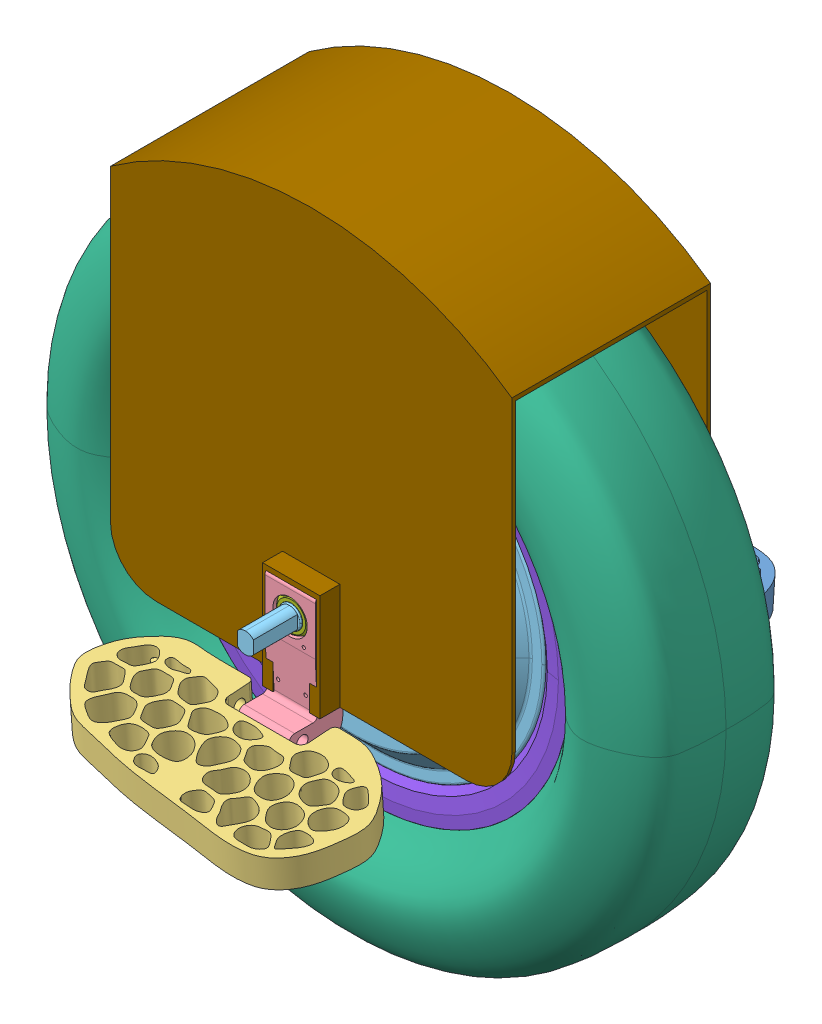
SolidWorks assembly ultimate_euc, configuration Default. Lengths in mm.
Overall size (694.47 596.2 979.3).
13 component instances, 9 part files, 13 mates.
Components (placement in the parent):
- Pedal subassembly-3: Pedal subassembly [Default] at (-129.9505 29.6673 -165.9174) x (0 -0.070149 -0.997537) z (1 0 0) size (667.71 138.3 546.6)
  - nylonove_pedals-1: nylonove_pedals [Default] at (-15.1911 -18.6389 -1.5417) size (641.26 25 546.6)
  - pedal holder solid-1: pedal holder solid [Default] at (-20.4641 -78.6432 -73.8896) x (1 0 0) z (0 -0.097811 0.995205) size (54.31 133.41 56.48)
- MirrorPedal subassembly-11: MirrorPedal subassembly [Default] at (-129.9505 29.6673 191.1591) x (0 -0.070149 0.997537) z (-1 0 0) size (157.12 138.3 257.31)
  - Mirrornylonove_pedals-1: Mirrornylonove_pedals [Default] at (-15.1911 -18.6389 1.5417) size (130.43 25 257.31)
  - Mirrorpedal holder solid-1: Mirrorpedal holder solid [Default] at (-20.4641 -78.6432 73.8896) x (1 0 0) z (0 0.097811 0.995205) size (54.31 133.41 56.48)
- 14in-1: 14in [Default] at (-128.8319 93.0936 9.2958) size (550.4 550.4 275) (flexible)
  - 14in QS273 6kW Scooter.stp[3]-1: 14in QS273 6kW Scooter.stp[3] [Default] at origin size (294.99 294.99 275)
  - 14in QS273 6kW Scooter.stp[5]-1: 14in QS273 6kW Scooter.stp[5] [Default] at origin size (550.4 550.4 140.93)
  - 14in QS273 6kW Scooter.stp[6]-1: 14in QS273 6kW Scooter.stp[6] [Default] at (0 0 -26.5) x (0.923728 0.383049 0) z (0 0 -1) size (31.1 30.88 15)
  - 14in QS273 6kW Scooter.stp[2]2-1: 14in QS273 6kW Scooter.stp[2]2 [Default] at origin size (350 350 83.1)
  - 14in QS273 6kW Scooter.stp[6]-2: 14in QS273 6kW Scooter.stp[6] [Default] at (0 0 33.15) size (31.1 30.88 15)
- Chassis-1: Chassis [Default] at (-203.8401 118.0936 165.2286) x (0 0 1) z (0 1 0) size (208 350 386)
Mates (geometry in assembly coordinates):
- Concentric1: concentric anti-aligned: cylinder of 14in-1/14in QS273 6kW Scooter.stp[3]-1 through (-128.8319 93.0936 134.0458) axis (0 0 1) radius 9; cylinder of MirrorPedal subassembly-11/Mirrorpedal holder solid-1 through (-128.8319 93.0936 134.2958) axis (0 0 -1) radius 7
- Concentric2: concentric aligned: cylinder of Pedal subassembly-3/pedal holder solid-1 through (-128.8319 93.0936 -109.0542) axis (0 0 1) radius 7; cylinder of 14in-1/14in QS273 6kW Scooter.stp[3]-1 through (-128.8319 93.0936 -102.4542) axis (0 0 1) radius 9
- Concentric3: concentric aligned: circle of 14in-1/14in QS273 6kW Scooter.stp[6]-1; cylinder of MirrorPedal subassembly-11/Mirrorpedal holder solid-1 through (-128.8319 93.0936 105.7958) axis (0 0 1) radius 15
- Concentric8: concentric aligned: cylinder of Pedal subassembly-3/pedal holder solid-1 through (-128.8319 93.0936 -80.5542) axis (0 0 -1) radius 15; circle of 14in-1/14in QS273 6kW Scooter.stp[6]-2
- Coincident2: coincident anti-aligned: plane of MirrorPedal subassembly-11/Mirrorpedal holder solid-1 through (-106.8319 94.0936 98.2958) normal (0 0 1); plane of 14in-1/14in QS273 6kW Scooter.stp[6]-1 through (-128.8319 93.0936 98.2958) normal (0 0 -1)
- Coincident3: coincident anti-aligned: plane of Pedal subassembly-3/pedal holder solid-1 through (-106.8319 94.0936 -73.0542) normal (0 0 -1); plane of 14in-1/14in QS273 6kW Scooter.stp[6]-2 through (-128.8319 93.0936 -73.0542) normal (0 0 1)
- Coincident4: coincident anti-aligned: plane of MirrorPedal subassembly-11/Mirrorpedal holder solid-1 through (-106.8319 18.0907 90.2958) normal (0 0 -1); plane of 14in-1/14in QS273 6kW Scooter.stp[3]-1 through (-103.8319 93.0936 90.2958) normal (0 0 1)
- Coincident5: coincident anti-aligned: plane of Pedal subassembly-3/pedal holder solid-1 through (-106.8319 18.0907 -65.0542) normal (0 0 1); plane of 14in-1/14in QS273 6kW Scooter.stp[3]-1 through (-109.8319 93.0936 -65.0542) normal (0 0 -1)
- Parallel1: parallel aligned: plane of 14in-1/14in QS273 6kW Scooter.stp[3]-1 through (-70.3319 93.0936 59.2958) normal (0 0 1)
- InPlace1: in place: plane of MirrorPedal subassembly-11/Mirrorpedal holder solid-1 through (-106.8319 118.0936 92.8958) normal (0 1 0); plane of ? through (0 118.0936 0) normal (0 1 0); moOrthogonalPlaneRef_w of MirrorPedal subassembly-11/Mirrorpedal holder solid-1 through (-106.8319 118.0936 92.8958) normal (0 1 0); plane of ? through (0 118.0936 0) normal (0 0 -1); plane of MirrorPedal subassembly-11/Mirrorpedal holder solid-1 through (-106.8319 118.0936 92.8958) normal (0 1 0); plane of ? through (0 118.0936 0) normal (1 0 0); plane of MirrorPedal subassembly-11/Mirrorpedal holder solid-1 through (-106.8319 118.0936 92.8958) normal (0 1 0); unknown of Chassis-1
- Coincident6: coincident aligned: plane of MirrorPedal subassembly-11/Mirrorpedal holder solid-1; plane of Chassis-1
- Coincident7: coincident aligned: moOrthogonalPlaneRef_w of MirrorPedal subassembly-11/Mirrorpedal holder solid-1 through (-203.8401 118.0936 165.2286) normal (1 0 0); plane of Chassis-1 through (-203.8401 118.0936 165.2286) normal (1 0 0)
- Coincident8: coincident anti-aligned: moOrthogonalPlaneRef_w of MirrorPedal subassembly-11/Mirrorpedal holder solid-1 through (-203.8401 118.0936 165.2286) normal (0 0 -1); plane of Chassis-1 through (-203.8401 118.0936 165.2286) normal (0 0 1)
